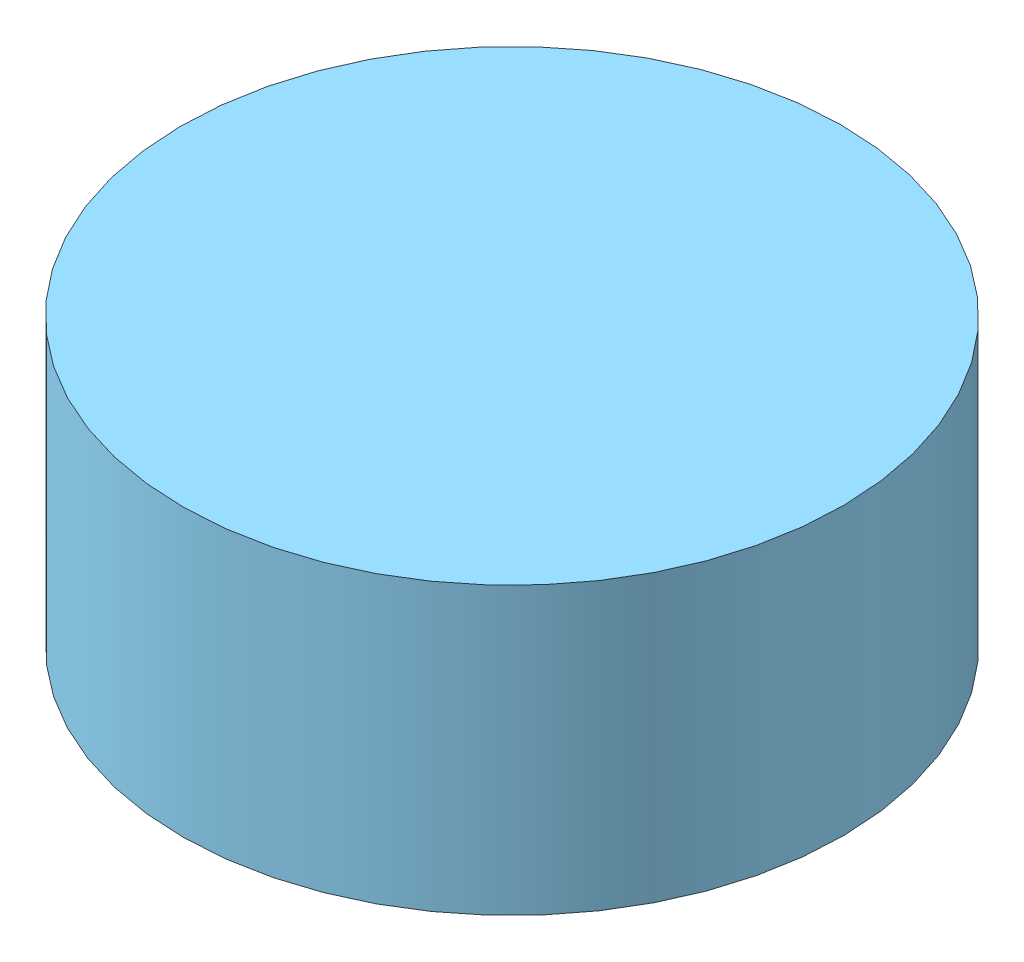
SolidWorks assembly Aeroshell - Copy, configuration Default. Lengths in mm.
Overall size (3020.73 1302.12 3020.73).
10 component instances, 10 part files, 0 mates.
Components (placement in the parent):
- TLS-1: TLS [Default] at (546.1998 194.1104 853.5417) size (100 100 207.41)
- MARCI-1: MARCI [Default] at (875.0511 241.327 764.8193) x (0 1 0) z (-1 0 0) size (91.44 139.7 71.12)
- MASPEX-1: MASPEX [Default] at (167.209 216.304 -1356.9014) size (1000 500 350)
- SEIS-1: SEIS [Default] at (220.1809 159.9248 678.7181) size (300 300 300)
- payloadStructure-1: payloadStructure [Default] at (0 101.113 -286.3686) x (0.999976 0 -0.006933) z (0.006933 0 0.999976) size (3000 1300 3000)
- Power-1: Power [Default] at (0 238.099 -286.3686) x (0.999963 0 0.008641) z (-0.008641 0 0.999963) size (560 1100 560)
- payloadStructureCap-1: payloadStructureCap [Default] at (0 98.9896 -282.8274) size (2800 100 2800)
- Telecommunications-1: Telecommunications [Default] at (-982.7536 220.0682 -363.8376) x (0 0 -1) z (1 0 0) size (1137.5 500 500)
- CDH-1: CDH [Default] at (887.8472 185.5639 40.0761) size (650 500 500)
- dinitrogenTeTank-3: dinitrogenTeTank [Default] at (-487.848 381.6959 325.1088) size (329.4 329.4 329.4)
